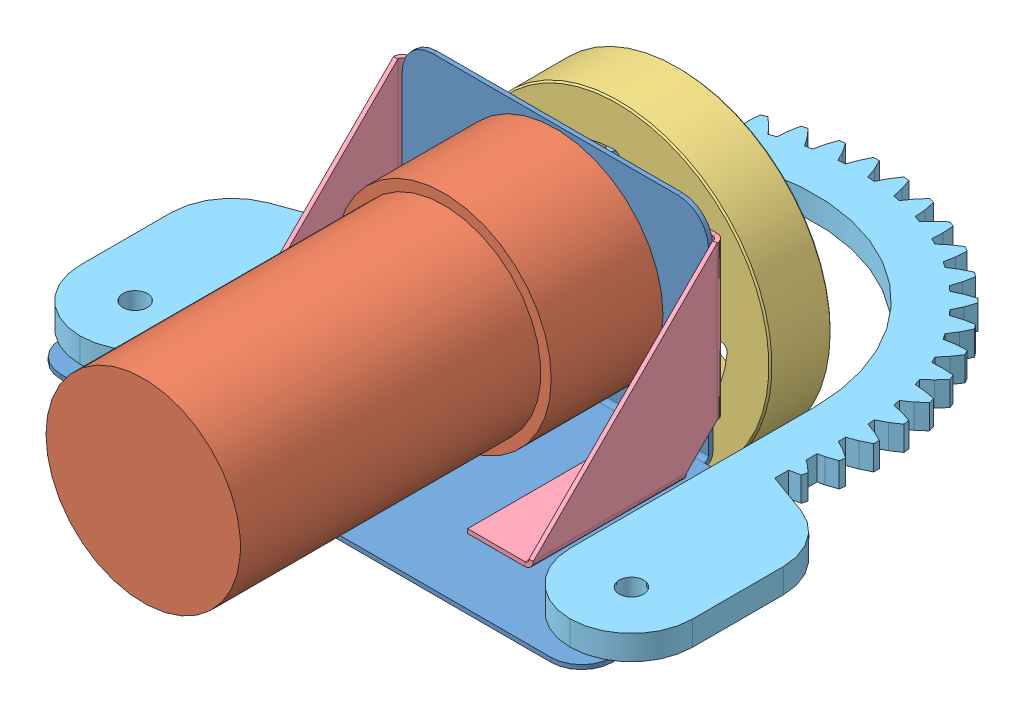
SolidWorks assembly 01 Motor Assembly, configuration v2. Lengths in mm.
Overall size (100 60.26 119.56).
6 component instances, 5 part files, 19 mates.
Components (placement in the parent):
- Motor Bracket-1: Motor Bracket [v2] at (0 0.7 0) size (90 35.7 41.4)
- Motor Barber Coleman geared-1: Motor Barber Coleman geared [Default] at (0 17.5692 -2.4628) x (0 0 1) z (-1 0 0) size (89.87 35.14 35.14)
- Wheel-1: Wheel [Default] at (0 8.8506 -30.813) x (-0.972576 -0.232587 0) z (0 0 -1) size (50 50 14)
- Gear Bracket-1: Gear Bracket [No Hole] at (-25.7 2.1 -20.7) x (0 0 1) z (0 1 0)
- Gear Bracket-3: Gear Bracket [No Hole] at (25.7 2.1 -20.7) x (0 1 0) z (0 0 1)
- Lower Turntable Gear-1: Lower Turntable Gear [Default] at (-47.0051 0.7 32.3496) x (1 0 0) z (0 1 0) size (100 90 4)
Mates (geometry in assembly coordinates):
- Coincident2: coincident anti-aligned: plane of Motor Bracket-1 through (0 0 0) normal (0 -1 0); plane of assembly through (0 0 0) normal (0 1 0)
- Coincident3: coincident aligned: plane of Motor Bracket-1 through (0 0.7 0) normal (1 0 0); plane of assembly through (0 0 0) normal (1 0 0)
- Coincident4: coincident aligned: plane of Motor Bracket-1 through (0 0.7 0) normal (0 0 1); plane of assembly through (0 0 0) normal (0 0 1)
- Coincident5: coincident anti-aligned: plane of Motor Bracket-1 through (0 0.7 -20.7) normal (0 0 1); plane of Motor Barber Coleman geared-1 through (0 17.5692 -20.7) normal (0 0 -1)
- Coincident6: coincident anti-aligned: plane of Motor Bracket-1 through (0 0.7 0) normal (1 0 0); plane of Motor Barber Coleman geared-1 through (0 17.5692 -2.4628) normal (-1 0 0)
- Concentric2: concentric aligned: cylinder of Motor Barber Coleman geared-1 through (0 8.8506 -43.306) axis (0 0 1) radius 2.3749; cylinder of Wheel-1 through (0 8.8506 -44.813) axis (0 0 1) radius 2.5
- Parallel1: parallel aligned: plane of Motor Barber Coleman geared-1 through (5.5361 11.9113 -28.32) normal (-0.232587 0.972576 0); plane of Wheel-1 through (1.9187 12.6511 -38.813) normal (-0.232587 0.972576 0)
- Coincident8: coincident: moEndPointRef_w of Motor Barber Coleman geared-1; plane of Wheel-1 through (0 8.8506 -35.813) normal (0 0 -1)
- Tangent1: tangent aligned: plane of Motor Bracket-1 through (0 0 0) normal (0 -1 0); cylinder of Motor Barber Coleman geared-1 through (0 17.5692 -20.7) axis (0 0 1) radius 17.5692
- Coincident9: coincident anti-aligned: plane of Motor Bracket-1 through (0 0.7 0) normal (0 1 0); plane of Gear Bracket-1 through (-25.7 0.7 -20.7) normal (0 -1 0)
- Coincident11: coincident anti-aligned: plane of Motor Bracket-1 through (0 0.7 -21.4) normal (0 0 -1); plane of Gear Bracket-1 through (-25.7 2.1 -21.4) normal (0 0 1)
- Coincident12: coincident aligned: line of Motor Bracket-1 through (-25 1.4 -21.4) axis (0 1 0); line of Gear Bracket-1 through (-25 7.1 -21.4) axis (0 1 0)
- Coincident13: coincident anti-aligned: plane of Motor Bracket-1 through (0 0.7 0) normal (0 1 0); plane of Gear Bracket-3 through (25.7 0.7 -20.7) normal (0 -1 0)
- Coincident14: coincident: plane of Motor Bracket-1 through (0 0.7 -21.4) normal (0 0 -1); line of Gear Bracket-3 through (25 32.1 -21.4) axis (0 -1 0)
- Coincident15: coincident aligned: line of Motor Bracket-1 through (25 30.7 -21.4) axis (0 -1 0); line of Gear Bracket-3 through (25 32.1 -21.4) axis (0 -1 0)
- Coincident16: coincident anti-aligned: plane of Motor Bracket-1 through (0 0.7 -21.4) normal (0 0 -1); plane of Gear Bracket-3 through (25.7 2.1 -21.4) normal (0 0 1)
- Coincident17: coincident anti-aligned: circle of Motor Bracket-1; cylinder of Lower Turntable Gear-1 through (-40.378 4.701 7.5) axis (0 -1 0) radius 2
- Parallel2: parallel aligned: plane of Lower Turntable Gear-1; plane of assembly through (0 0 0) normal (1 0 0)
- Coincident21: coincident anti-aligned: plane of Motor Bracket-1 through (0 0.7 0) normal (0 1 0); plane of Lower Turntable Gear-1 through (-47.0051 0.7 32.3496) normal (0 -1 0)
